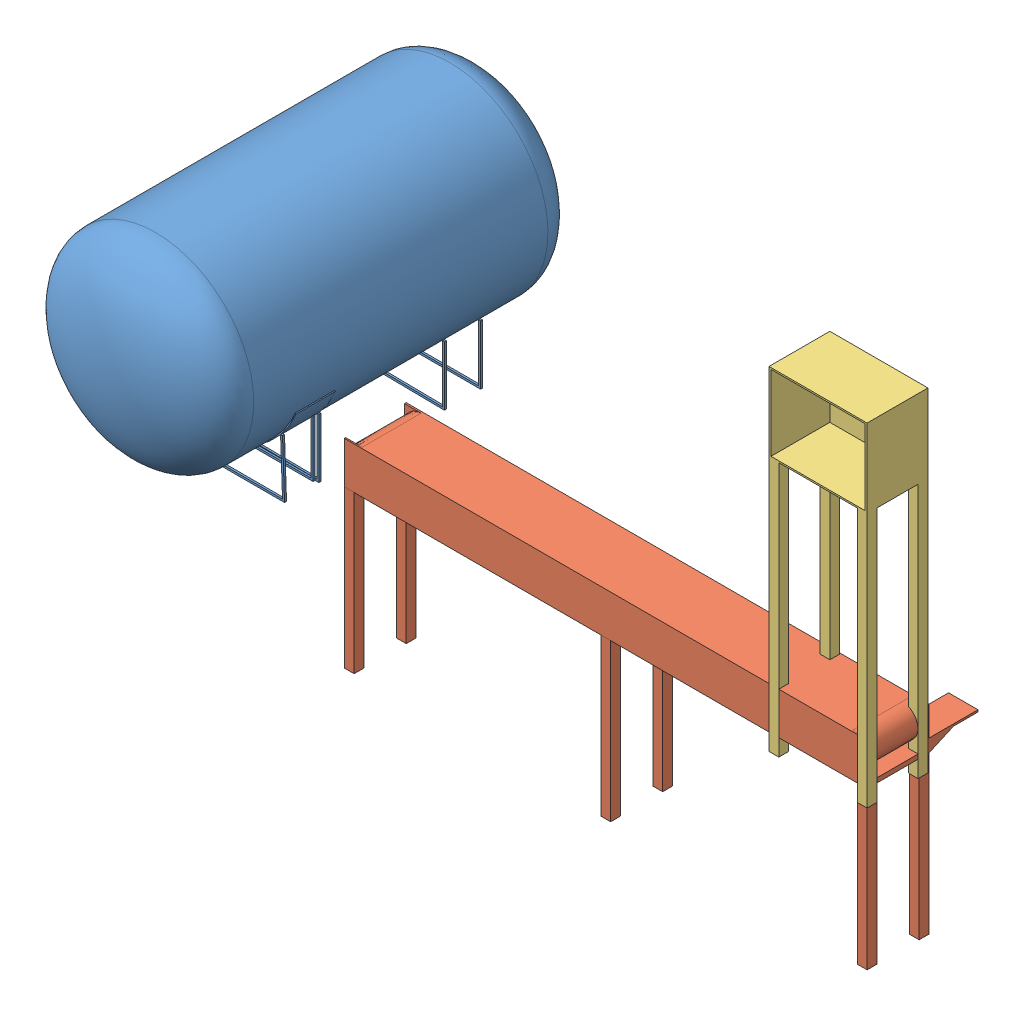
SolidWorks assembly Assem3, configuration Default. Lengths in mm.
Overall size (2897.16 2672.19 2045.51).
5 component instances, 3 part files, 0 mates.
Components (placement in the parent):
- bcd-1: bcd [Default] at (1743.7584 1541.6781 1854.0798) size (2897.16 2672.19 2045.51)
  - boiler wit belt-1: boiler wit belt [Default] at (-142.2265 782.2575 778.5494) size (2897.16 2672.19 2045.51)
    - boiler-1: boiler [Default] at (-337.5189 1351.3906 1936.8974) size (1000 1113.97 2000)
    - brick_conveyer-1: brick_conveyer [Default] at (1784.6375 113.4237 1450.0152) x (0 0 -1) z (1 0 0) size (565.37 1014.22 2665)
  - control_box-1: control_box [Default] at (1667.411 2175.7674 1935.3104) size (500 1700 310)
